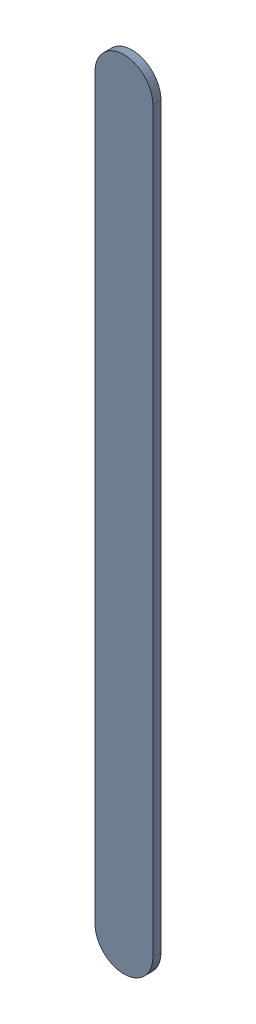
SolidWorks assembly Track (8.493mm,33.107mm)(8.493mm,36.353mm) on Bottom Layer, configuration Predeterminado. Lengths in mm.
Overall size (0.25 3.5 0.04).
2 component instances, 1 part files, 0 mates.
Components (placement in the parent):
- Track (8.493mm,33.107mm)(8.493mm,36.353mm) on Bottom Layer-1-1: Track (8.493mm,33.107mm)(8.493mm,36.353mm) on Bottom Layer-1 [Predeterminado] at (-68.317 -44.187 -0.4013) size (0.25 3.5 0.04)
  - Track (8.493mm,33.107mm)(8.493mm,36.353mm) on Bottom Layer-Part-1-1: Track (8.493mm,33.107mm)(8.493mm,36.353mm) on Bottom Layer-Part-1 [Predeterminado] at origin size (0.25 3.5 0.04)
